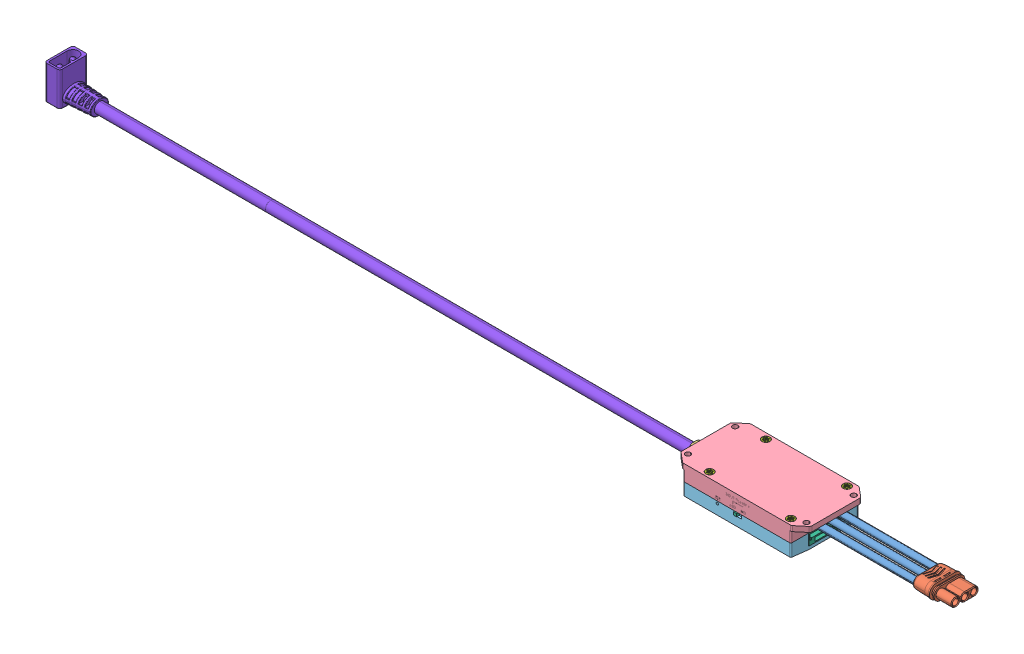
SolidWorks assembly C620 Motor Controller, configuration Default. Lengths in mm.
Overall size (345.36 15.69 26.13).
15 component instances, 8 part files, 0 mates.
Components (placement in the parent):
- RoboMaster C620 Brushless DC Motor Speed Controller(2)^C620 Motor Controller-1: RoboMaster C620 Brushless DC Motor Speed Controller(2)^C620 Motor Controller [Default] at origin size (345.36 15.69 26.13) (virtual)
  - 9^RoboMaster C620 Brushless DC Motor Speed Controller(2)_C620 Motor Controller-1: 9^RoboMaster C620 Brushless DC Motor Speed Controller(2)_C620 Motor Controller [Default] at (63.0501 2 0) x (0 0 1) z (1 0 0) size (12.31 5.31 60.01) (virtual)
    - 14^9_RoboMaster C620 Brushless DC Motor Speed Controller(2)_C620 Motor Controller-1: 14^9_RoboMaster C620 Brushless DC Motor Speed Controller(2)_C620 Motor Controller [Default] at (4 0 -0.7) size (2.5 2.5 50) (virtual)
    - 14^9_RoboMaster C620 Brushless DC Motor Speed Controller(2)_C620 Motor Controller-2: 14^9_RoboMaster C620 Brushless DC Motor Speed Controller(2)_C620 Motor Controller [Default] at (0 0 -0.7) x (0.422263 0.906473 0) z (0 0 1) size (2.5 2.5 50) (virtual)
    - 14^9_RoboMaster C620 Brushless DC Motor Speed Controller(2)_C620 Motor Controller-3: 14^9_RoboMaster C620 Brushless DC Motor Speed Controller(2)_C620 Motor Controller [Default] at (-4 0 -0.7) size (2.5 2.5 50) (virtual)
    - 1^9_RoboMaster C620 Brushless DC Motor Speed Controller(2)_C620 Motor Controller-1: 1^9_RoboMaster C620 Brushless DC Motor Speed Controller(2)_C620 Motor Controller [Default] at (-18.7519 0 2.7064) x (-1 0 0) z (0 0 1) size (12.31 5.31 14.5) (virtual)
  - 6^RoboMaster C620 Brushless DC Motor Speed Controller(2)_C620 Motor Controller-1: 6^RoboMaster C620 Brushless DC Motor Speed Controller(2)_C620 Motor Controller [Default] at (-2.2 39.826 -7.4409) x (0 -0.431667 0.902033) z (-1 0 0) size (8.67 8.67 10.5) (virtual)
  - 7^RoboMaster C620 Brushless DC Motor Speed Controller(2)_C620 Motor Controller-1: 7^RoboMaster C620 Brushless DC Motor Speed Controller(2)_C620 Motor Controller [Default] at (-1.7 0.6 0) size (49.4 6 25.8) (virtual)
  - 8^RoboMaster C620 Brushless DC Motor Speed Controller(2)_C620 Motor Controller-1: 8^RoboMaster C620 Brushless DC Motor Speed Controller(2)_C620 Motor Controller [Default] at (-1.7 -0.6 0) x (0 -1 0) z (0 0 1) size (6.5 41 25.8) (virtual)
  - 2^RoboMaster C620 Brushless DC Motor Speed Controller(2)_C620 Motor Controller-1: 2^RoboMaster C620 Brushless DC Motor Speed Controller(2)_C620 Motor Controller [Default] at (15.6004 -0.6014 9.8) x (0 0 -1) z (0 1 0) size (24.83 40.8 4.35) (virtual)
  - 5^RoboMaster C620 Brushless DC Motor Speed Controller(2)_C620 Motor Controller-1: 5^RoboMaster C620 Brushless DC Motor Speed Controller(2)_C620 Motor Controller [Default] at (16.6 -3.6 -10.7) x (-0.36263 0 0.931933) z (-0.931933 0 -0.36263) size (3 9 3) (virtual)
  - 5^RoboMaster C620 Brushless DC Motor Speed Controller(2)_C620 Motor Controller-2: 5^RoboMaster C620 Brushless DC Motor Speed Controller(2)_C620 Motor Controller [Default] at (16.6 -3.6 10.7) size (3 9 3) (virtual)
  - 5^RoboMaster C620 Brushless DC Motor Speed Controller(2)_C620 Motor Controller-3: 5^RoboMaster C620 Brushless DC Motor Speed Controller(2)_C620 Motor Controller [Default] at (-14.3 -3.6 10.7) size (3 9 3) (virtual)
  - 5^RoboMaster C620 Brushless DC Motor Speed Controller(2)_C620 Motor Controller-4: 5^RoboMaster C620 Brushless DC Motor Speed Controller(2)_C620 Motor Controller [Default] at (-14.3 -3.6 -10.7) size (3 9 3) (virtual)
  - 10^RoboMaster C620 Brushless DC Motor Speed Controller(2)_C620 Motor Controller-1: 10^RoboMaster C620 Brushless DC Motor Speed Controller(2)_C620 Motor Controller [Default] at (-177.4931 0.4104 -3.9137) x (1 0 0) z (0 -1 0) size (250.81 10.82 13.76) (virtual)
